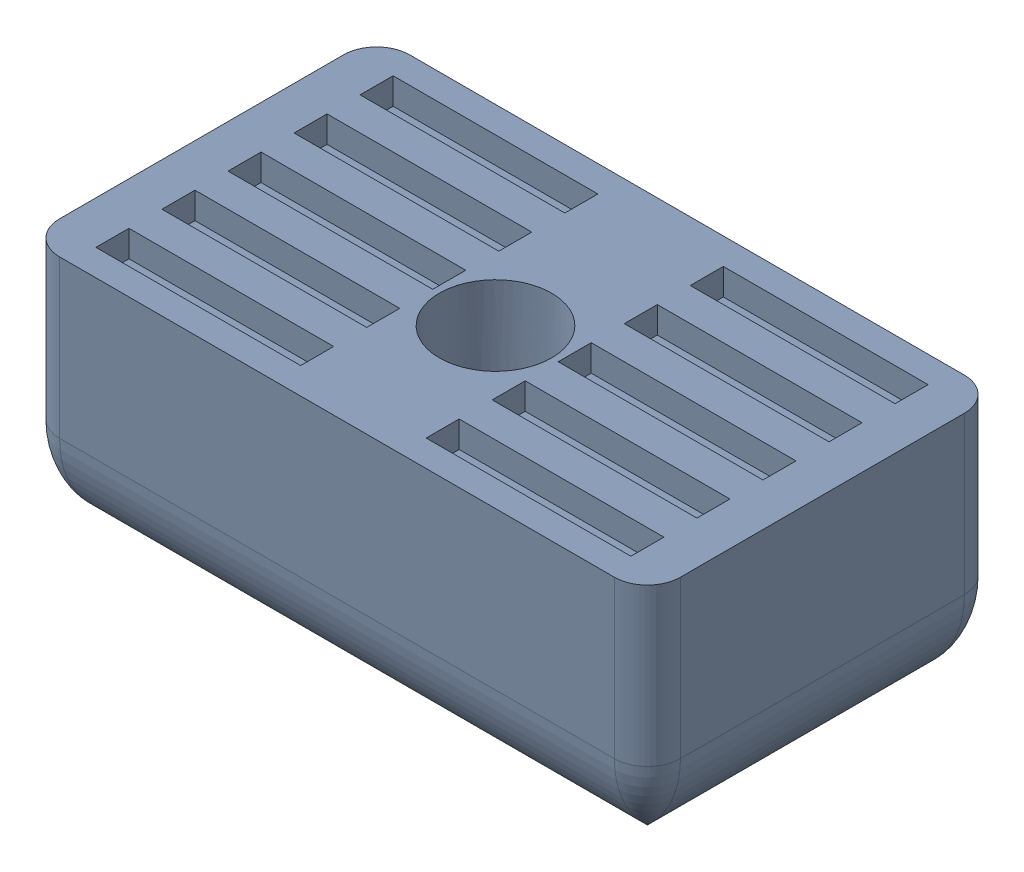
SolidWorks assembly Belt Clip_1, configuration Default. Lengths in mm.
Overall size (18.8 7 10.6).
2 component instances, 2 part files, 0 mates.
Components (placement in the parent):
- Belt Clip_1-1: Belt Clip_1 [Default] at origin size (18.8 7 10.6)
- M3 Threaded Insert (1)-1: M3 Threaded Insert (1) [Default] at (-82.7703 134.942 -16.1565) x (1 0 0) z (0 -1 0) size (5 5 3.85)
